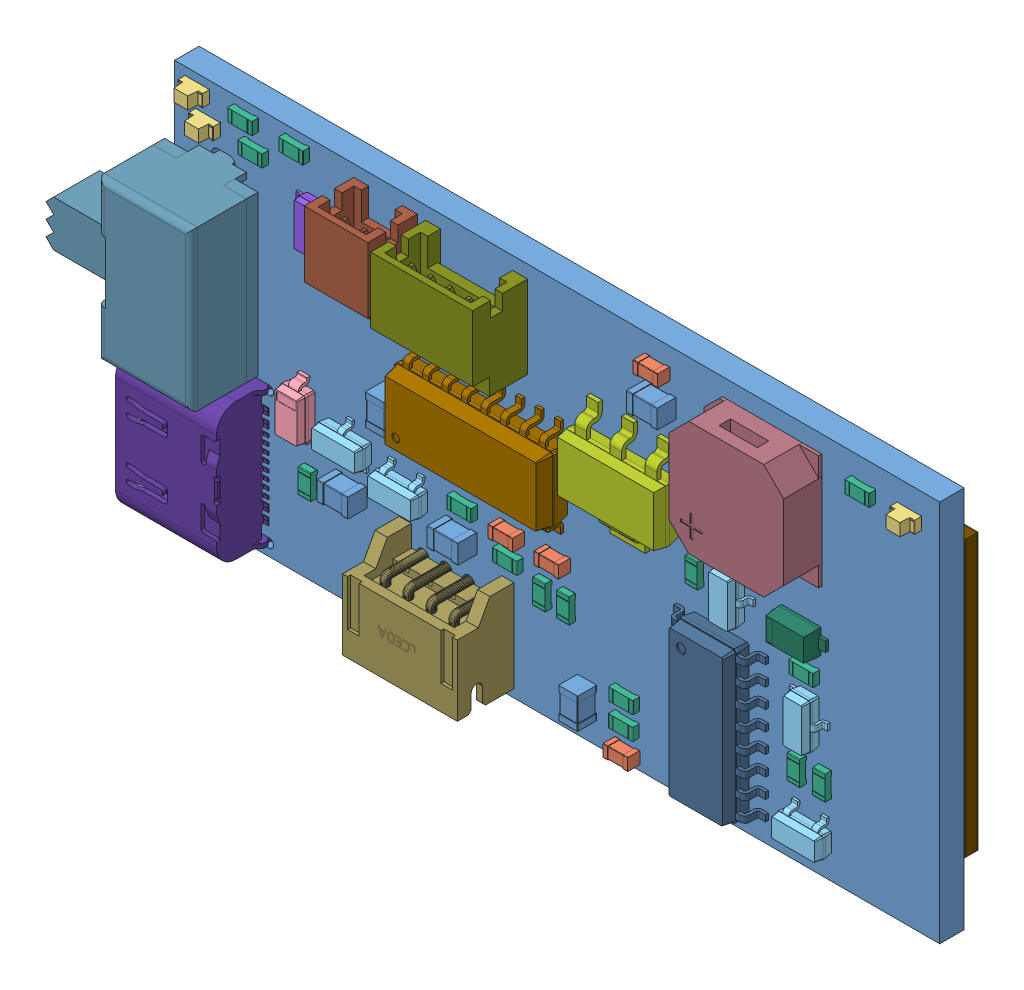
SolidWorks assembly GripMeter_PCBA, configuration Predeterminado. Lengths in mm.
Overall size (53.85 25 9.71).
91 component instances, 19 part files, 0 mates.
Components (placement in the parent):
- C_0805_2012Metric-1: C_0805_2012Metric [Predeterminado] at (111.61 -143.4 1.65) x (-1 0 0) z (0 0 1) size (2 1.25 1.25)
  - SOLID-1: SOLID [Predeterminado] at origin size (2 1.25 1.25)
- C_0805_2012Metric-2: C_0805_2012Metric [Predeterminado] at (131.83 -128.25 1.65) size (2 1.25 1.25)
  - SOLID-1: SOLID [Predeterminado] at origin size (2 1.25 1.25)
- C_0603_1608Metric-1: C_0603_1608Metric [Predeterminado] at (131.61 -126.52 1.65) size (1.6 0.8 0.8)
  - SOLID_2-1: SOLID_2 [Predeterminado] at origin size (1.6 0.8 0.8)
- C_0805_2012Metric-3: C_0805_2012Metric [Predeterminado] at (118.81 -142.41 1.65) size (2 1.25 1.25)
  - SOLID-1: SOLID [Predeterminado] at origin size (2 1.25 1.25)
- C_0603_1608Metric-2: C_0603_1608Metric [Predeterminado] at (122.13 -140.57 1.65) size (1.6 0.8 0.8)
  - SOLID_2-1: SOLID_2 [Predeterminado] at origin size (1.6 0.8 0.8)
- C_0603_1608Metric-3: C_0603_1608Metric [Predeterminado] at (125.13 -140.58 1.65) size (1.6 0.8 0.8)
  - SOLID_2-1: SOLID_2 [Predeterminado] at origin size (1.6 0.8 0.8)
- C_0805_2012Metric-4: C_0805_2012Metric [Predeterminado] at (114.38 -137.23 1.65) x (0 1 0) z (0 0 1) size (2 1.25 1.25)
  - SOLID-1: SOLID [Predeterminado] at origin size (2 1.25 1.25)
- LED_0603_1608Metric-1: LED_0603_1608Metric [Predeterminado] at (102.26 -127.36 1.65) size (1.6 0.8 1.1)
  - SOLID_3-1: SOLID_3 [Predeterminado] at origin size (1.6 0.8 1.1)
- D_SOD-123-1: D_SOD-123 [Predeterminado] at (108.58 -140.29 1.65) x (0 -1 0) z (0 0 1) size (3.8 1.6 1.25)
  - SOLID_4-1: SOLID_4 [Predeterminado] at origin size (3.8 1.6 1.25)
- SOT-23-1: SOT-23 [Predeterminado] at (141.62 -141.23 1.65) size (2.5 3 1.2)
  - SOLID_5-1: SOLID_5 [Predeterminado] at origin size (2.5 3 1.2)
- SOT-23-2: SOT-23 [Predeterminado] at (141.66 -147.65 1.65) x (0 -1 0) z (0 0 1) size (2.5 3 1.2)
  - SOLID_5-1: SOLID_5 [Predeterminado] at origin size (2.5 3 1.2)
- SOT-23-3: SOT-23 [Predeterminado] at (111.6 -140.68 1.65) x (0 1 0) z (0 0 1) size (2.5 3 1.2)
  - SOLID_5-1: SOLID_5 [Predeterminado] at origin size (2.5 3 1.2)
- R_0603_1608Metric-1: R_0603_1608Metric [Predeterminado] at (140.93 -144.46 1.65) x (0 -1 0) z (0 0 1) size (1.6 0.8 0.45)
  - SOLID_6-1: SOLID_6 [Predeterminado] at origin size (1.6 0.8 0.45)
- R_0603_1608Metric-2: R_0603_1608Metric [Predeterminado] at (141.425 -138.75 1.65) x (-1 0 0) z (0 0 1) size (1.6 0.8 0.45)
  - SOLID_6-1: SOLID_6 [Predeterminado] at origin size (1.6 0.8 0.45)
- R_0603_1608Metric-3: R_0603_1608Metric [Predeterminado] at (142.59 -144.46 1.65) x (0 -1 0) z (0 0 1) size (1.6 0.8 0.45)
  - SOLID_6-1: SOLID_6 [Predeterminado] at origin size (1.6 0.8 0.45)
- R_0603_1608Metric-4: R_0603_1608Metric [Predeterminado] at (108.09 -125.85 1.65) size (1.6 0.8 0.45)
  - SOLID_6-1: SOLID_6 [Predeterminado] at origin size (1.6 0.8 0.45)
- R_0603_1608Metric-5: R_0603_1608Metric [Predeterminado] at (105.42 -127.35 1.65) x (-1 0 0) z (0 0 1) size (1.6 0.8 0.45)
  - SOLID_6-1: SOLID_6 [Predeterminado] at origin size (1.6 0.8 0.45)
- R_0603_1608Metric-6: R_0603_1608Metric [Predeterminado] at (108.98 -144.25 1.65) x (0 -1 0) z (0 0 1) size (1.6 0.8 0.45)
  - SOLID_6-1: SOLID_6 [Predeterminado] at origin size (1.6 0.8 0.45)
- R_0603_1608Metric-7: R_0603_1608Metric [Predeterminado] at (124.3 -142.84 1.65) x (0 -1 0) z (0 0 1) size (1.6 0.8 0.45)
  - SOLID_6-1: SOLID_6 [Predeterminado] at origin size (1.6 0.8 0.45)
- R_0603_1608Metric-8: R_0603_1608Metric [Predeterminado] at (125.86 -142.8 1.65) x (0 -1 0) z (0 0 1) size (1.6 0.8 0.45)
  - SOLID_6-1: SOLID_6 [Predeterminado] at origin size (1.6 0.8 0.45)
- R_0603_1608Metric-9: R_0603_1608Metric [Predeterminado] at (119.075 -140.6 1.65) size (1.6 0.8 0.45)
  - SOLID_6-1: SOLID_6 [Predeterminado] at origin size (1.6 0.8 0.45)
- R_0603_1608Metric-10: R_0603_1608Metric [Predeterminado] at (122.06 -142.08 1.65) size (1.6 0.8 0.45)
  - SOLID_6-1: SOLID_6 [Predeterminado] at origin size (1.6 0.8 0.45)
- SOT-223-1: SOT-223 [Predeterminado] at (129.92 -133.71 1.65) x (0 -1 0) z (0 0 1) size (7 6.5 1.7)
  - SOLID_7-1: SOLID_7 [Predeterminado] at origin size (7 6.5 1.7)
- TSOT-23-5-1: TSOT-23-5 [Predeterminado] at (109.52 -129.37 1.65) x (-1 0 0) z (0 0 1) size (2.8 2.9 0.95)
  - SOLID_8-1: SOLID_8 [Predeterminado] at origin size (2.8 2.9 0.95)
- SOP-16_4.4x10.4mm_P1.27mm-1: SOP-16_4.4x10.4mm_P1.27mm [Predeterminado] at (120.83 -135.77 1.65) x (0 1 0) z (0 0 1) size (6.4 10.4 2.1)
  - SOLID_9-1: SOLID_9 [Predeterminado] at origin size (6.4 10.4 2.1)
- SOIC-16_3.9x9.9mm_P1.27mm-1: SOIC-16_3.9x9.9mm_P1.27mm [Predeterminado] at (135.86 -143.9 1.65) size (6 9.9 1.75)
  - SOLID_10-1: SOLID_10 [Predeterminado] at origin size (6 9.9 1.75)
- df13-2p-1_25ds_50_-1: df13-2p-1_25ds_50_ [Predeterminado] at (98.16 -128.54 28.65) x (0 0 1) z (-1 0 0) size (5.9 5.4 4.15)
  - COMPOUND-1: COMPOUND [Predeterminado] at origin size (5.9 5.4 4.15)
- jst_zh_1_5mm_4d-1: jst_zh_1_5mm_4d [Predeterminado] at (118.48 -146.42 1.65) size (7.5 6 6.48)
  - COMPOUND_2-1: COMPOUND_2 [Predeterminado] at origin size (7.5 6 6.48)
- LED_0603_1608Metric-2: LED_0603_1608Metric [Predeterminado] at (101.56 -125.84 1.65) x (-1 0 0) z (0 0 1) size (1.6 0.8 1.1)
  - SOLID_3-1: SOLID_3 [Predeterminado] at origin size (1.6 0.8 1.1)
- SOT-23-4: SOT-23 [Predeterminado] at (115.26 -141.56 1.65) x (0 -1 0) z (0 0 1) size (2.5 3 1.2)
  - SOLID_5-1: SOLID_5 [Predeterminado] at origin size (2.5 3 1.2)
- R_0603_1608Metric-11: R_0603_1608Metric [Predeterminado] at (104.75 -125.85 1.65) size (1.6 0.8 0.45)
  - SOLID_6-1: SOLID_6 [Predeterminado] at origin size (1.6 0.8 0.45)
- User Library-YX7525P-1: User Library-YX7525P [Predeterminado] at (138.6 -129.83 1.65) size (7.56 7.56 2.51)
  - SOLID_11-1: SOLID_11 [Predeterminado] at origin size (7.56 7.56 2.51)
- LED_0603_1608Metric-3: LED_0603_1608Metric [Predeterminado] at (148.09 -126.72 1.65) x (-1 0 0) z (0 0 1) size (1.6 0.8 1.1)
  - SOLID_3-1: SOLID_3 [Predeterminado] at origin size (1.6 0.8 1.1)
- R_0603_1608Metric-12: R_0603_1608Metric [Predeterminado] at (145.09 -126.72 1.65) size (1.6 0.8 0.45)
  - SOLID_6-1: SOLID_6 [Predeterminado] at origin size (1.6 0.8 0.45)
- User Library-SK-22D02-PG4-1: User Library-SK-22D02-PG4 [Predeterminado] at (103.2 -134.14 1.65) x (0 1 0) z (0 0 1) size (10.4 10.1 7.6)
  - COMPOUND_3-1: COMPOUND_3 [Predeterminado] at origin size (10.4 10.1 7.6)
- C_0805_2012Metric-5: C_0805_2012Metric [Predeterminado] at (127.01 -147.52 1.65) x (0 -1 0) z (0 0 1) size (2 1.25 1.25)
  - SOLID-1: SOLID [Predeterminado] at origin size (2 1.25 1.25)
- R_0603_1608Metric-13: R_0603_1608Metric [Predeterminado] at (129.64 -147.69 1.65) x (-1 0 0) z (0 0 1) size (1.6 0.8 0.45)
  - SOLID_6-1: SOLID_6 [Predeterminado] at origin size (1.6 0.8 0.45)
- R_0603_1608Metric-14: R_0603_1608Metric [Predeterminado] at (129.65 -146.17 1.65) size (1.6 0.8 0.45)
  - SOLID_6-1: SOLID_6 [Predeterminado] at origin size (1.6 0.8 0.45)
- D_SOD-123F-1: D_SOD-123F [Predeterminado] at (141.02 -136.69 1.65) size (3.5 1.6 1.1)
  - SOLID_12-1: SOLID_12 [Predeterminado] at origin size (3.5 1.6 1.1)
- SOT-23-5: SOT-23 [Predeterminado] at (136.76 -136.63 1.65) size (2.5 3 1.2)
  - SOLID_5-1: SOLID_5 [Predeterminado] at origin size (2.5 3 1.2)
- R_0603_1608Metric-15: R_0603_1608Metric [Predeterminado] at (134.25 -136.63 1.65) x (0 1 0) z (0 0 1) size (1.6 0.8 0.45)
  - SOLID_6-1: SOLID_6 [Predeterminado] at origin size (1.6 0.8 0.45)
- df13-4p-1_25ds_50_-1: df13-4p-1_25ds_50_ [Predeterminado] at (105.5 -128.48 29.15) x (0 0 1) z (-1 0 0) size (5.9 5.4 6.65)
  - COMPOUND_4-1: COMPOUND_4 [Predeterminado] at origin size (5.9 5.4 6.65)
- DX07S016JA1-V1_JAE_Proprietary-1: DX07S016JA1-V1_JAE_Proprietary [Predeterminado] at (103.97 -144.91 3.15) x (0 -1 0) z (0 0 1) size (8.94 6.9 4.06)
  - SOLID_13-1: SOLID_13 [Predeterminado] at origin size (8.94 6.9 4.06)
- C_0603_1608Metric-4: C_0603_1608Metric [Predeterminado] at (129.65 -149.21 1.65) x (-1 0 0) z (0 0 1) size (1.6 0.8 0.8)
  - SOLID_2-1: SOLID_2 [Predeterminado] at origin size (1.6 0.8 0.8)
- User Library-ESP321-1: User Library-ESP321 [Predeterminado] at (137.2 -137 -0.05) x (0 1 0) z (0 0 -1) size (18 25.5 2.92)
  - COMPOUND_5-1: COMPOUND_5 [Predeterminado] at origin size (18 25.5 2.92)
- _autosave-GripMeter PCB-1: _autosave-GripMeter PCB [Predeterminado] at origin size (50 25 1.6)
